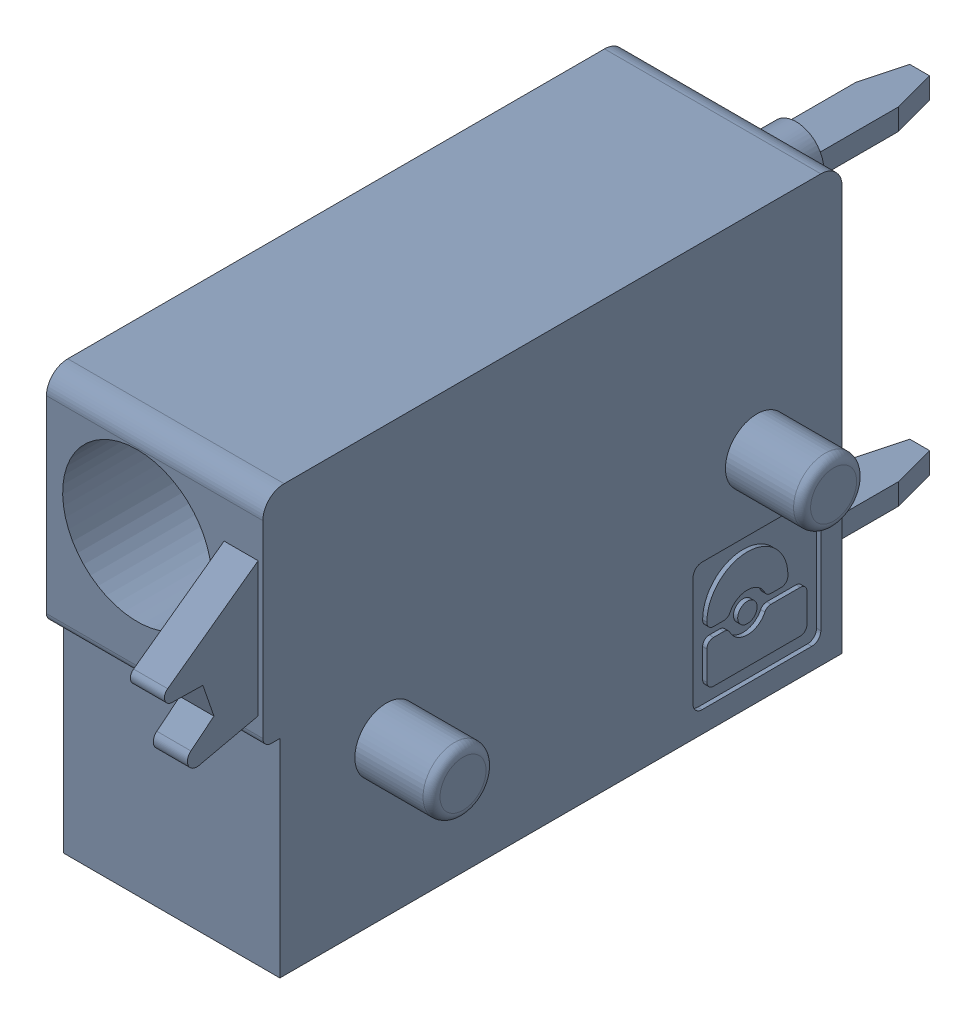
SolidWorks assembly J42, configuration Default. Lengths in mm.
Overall size (6.88 10 19.2).
2 component instances, 1 part files, 0 mates.
Components (placement in the parent):
- 1790348-1: 1790348 [Default] at (121.2851 -7.6199 0) x (0 1 0) z (1 0 0) size (10 19.2 6.88)
  - ffkds-v2-5.08-1: ffkds-v2-5.08 [Default] at (-23.7414 -38.158 -2.54) x (0 -1 0) z (0 0 1) size (19.2 10 6.88)
